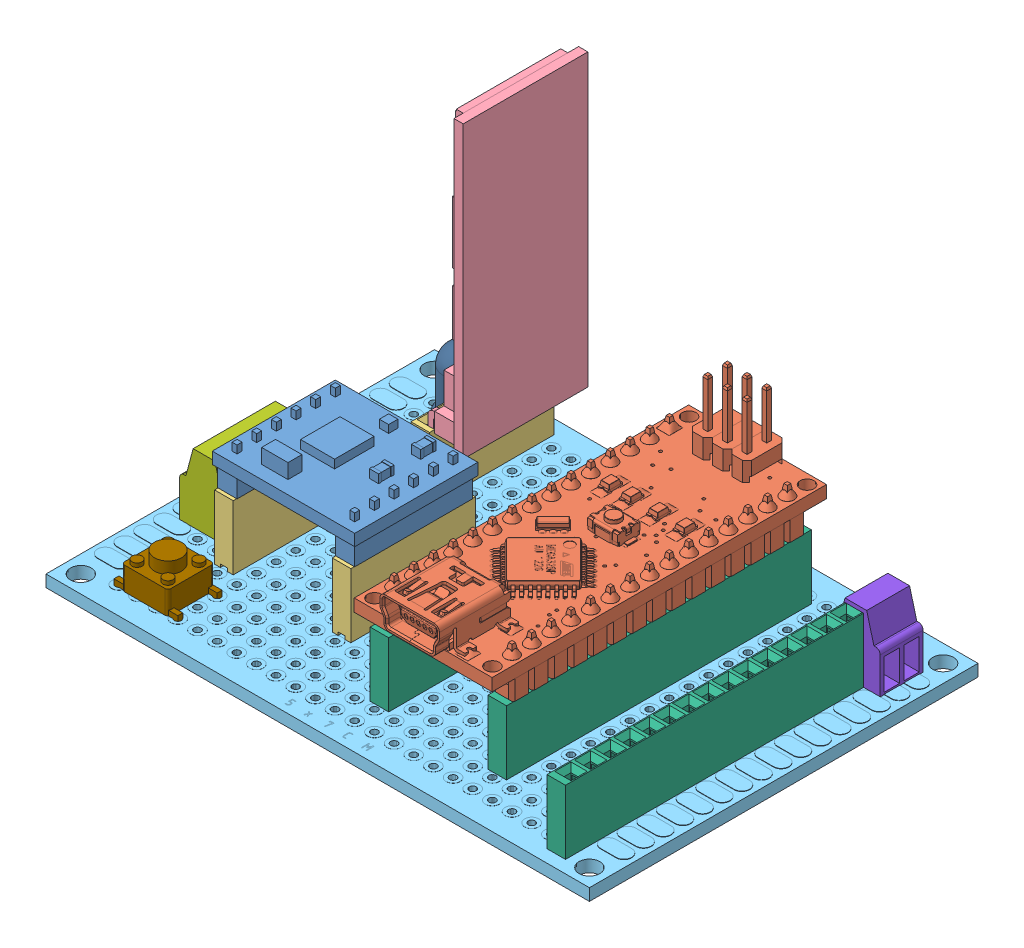
SolidWorks assembly PCB assembly, configuration Default. Lengths in mm.
Overall size (70.2 48.6 50.2).
14 component instances, 10 part files, 20 mates.
Components (placement in the parent):
- DRV8833-1: DRV8833 [Default] at (-16.49 13.955 5.08) size (18.4 11.9 15.9)
- Arduino Nano-1: Arduino Nano [Default] at (16.8088 23.6188 0.3902) x (0 0 1) z (-1 0 0) size (44.95 20.74 17.81)
- Header6P-1: Header6P [Default] at (-24.09 1.555 -1.27) x (0 0 1) z (0 1 0) size (16.1 2.4 11.5)
- Header6P-2: Header6P [Default] at (-8.89 1.555 -1.27) x (0 0 1) z (0 1 0) size (16.1 2.4 11.5)
- HC-05-2: HC-05 [Varsayılan] at (-13.49 46.555 -23.29) x (0 -1 0) z (-1 0 0) size (42.6 16.1 5.9)
- Header6P-3: Header6P [Default] at (-19.04 1.555 -21.59) x (0 0 1) z (0 1 0) size (16.1 2.4 11.5)
- PCB 50 x 70-1: PCB 50 x 70 [Default] x (1 0 0) z (0 1 0) size (70.2 50.2 1.66)
- Header15P-1: Header15P [Default] at (1.2888 2.355 16.51) x (0 0 1) z (0 1 0) size (39.38 2.4 11.5)
- Header15P-2: Header15P [Default] at (16.51 2.355 16.51) x (0 0 1) z (0 1 0) size (39.38 2.4 11.5)
- Header15P-3: Header15P [Default] at (29.21 2.355 -13.97) x (0 0 -1) z (0 1 0) size (39.38 2.4 11.5)
- ScrewTerminal x 4-1: ScrewTerminal x 4 [Default] at (-29.4 1.555 5.08) x (0 0 1) z (-1 0 0) size (10.62 12.4 6.3)
- ScrewTerminal x 2-1: ScrewTerminal x 2 [Default] at (29.41 1.555 -17.78) x (0 0 -1) z (1 0 0) size (5.54 12.4 6.3)
- Push button-1: Push button [Default] at (-25.39 1.555 19.05) size (8.26 7.7 6)
- Led-1: Led [Default] at (-25.39 1.555 -19.05) size (5.8 11.9 5.8)
Mates (geometry in assembly coordinates):
- ProfileCenter6: profile center = 5.6 mm aligned: plane of DRV8833-1 through (45.36 34.005 5.08) normal (0 -1 0); plane of Header6P-1 through (37.76 28.405 11.605) normal (0 -1 0)
- ProfileCenter7: profile center = 5.6 mm aligned: plane of Header6P-2 through (52.96 28.405 11.605) normal (0 -1 0); plane of DRV8833-1 through (45.36 34.005 5.08) normal (0 -1 0)
- ProfileCenter9: profile center = 5.6 mm aligned: plane of HC-05-2 through (48.36 34.005 -23.29) normal (0 -1 0); plane of Header6P-3 through (42.81 28.405 -8.715) normal (0 -1 0)
- ProfileCenter10: profile center = 3.5 mm aligned: plane of Header15P-1 through (63.1388 28.405 16.51) normal (0 -1 0); plane of Arduino Nano-1 through (63.1388 31.905 16.51) normal (0 -1 0)
- ProfileCenter11: profile center = 3.5 mm aligned: plane of Header15P-2 through (78.36 28.405 16.51) normal (0 -1 0); plane of Arduino Nano-1 through (78.36 31.905 16.51) normal (0 -1 0)
- ProfileCenter12: profile center = 3.2 mm anti-aligned: plane of Header15P-2 through (78.36 28.405 16.51) normal (0 -1 0); circle of PCB 50 x 70-1
- ProfileCenter13: profile center = 3.2 mm anti-aligned: plane of Header6P-2 through (52.96 28.405 11.605) normal (0 -1 0); circle of PCB 50 x 70-1
- ProfileCenter15: profile center = 3.2 mm anti-aligned: plane of Header15P-3 through (91.06 28.405 -13.97) normal (0 -1 0); circle of PCB 50 x 70-1
- Parallel2: parallel aligned: plane of Header15P-2 through (17.71 41.0672 15.24) normal (1 0 0); plane of Header15P-3 through (30.41 41.0672 -12.7) normal (1 0 0)
- Parallel3: parallel aligned: plane of Header6P-3 through (-20.24 33.5672 -23.09) normal (-1 0 0); plane of Header15P-1 through (0.0888 41.0672 15.24) normal (-1 0 0)
- ProfileCenter19: profile center = 3.6 mm anti-aligned: plane of ScrewTerminal x 4-1 through (32.45 28.005 5.08) normal (0 -1 0); circle of PCB 50 x 70-1
- Parallel6: parallel anti-aligned: plane of ScrewTerminal x 4-1 through (-29.4 33.5672 5.08) normal (-1 0 0); plane of PCB 50 x 70-1 through (0 32.0122 0) normal (1 0 0)
- ProfileCenter20: profile center = 3.6 mm anti-aligned: plane of ScrewTerminal x 2-1 through (91.26 28.005 -17.78) normal (0 -1 0); circle of PCB 50 x 70-1
- Parallel7: parallel aligned: plane of PCB 50 x 70-1 through (0 32.0122 0) normal (0 0 -1); plane of ScrewTerminal x 2-1 through (29.41 33.5672 -17.78) normal (0 0 -1)
- ProfileCenter21: profile center = 3.2 mm anti-aligned: plane of Push button-1 through (36.46 28.405 19.05) normal (0 -1 0); circle of PCB 50 x 70-1
- ProfileCenter22: profile center = 3.2 mm aligned: plane of Led-1 through (37.73 28.405 -19.05) normal (0 -1 0); circle of PCB 50 x 70-1
- ProfileCenter23: profile center = 3.2 mm anti-aligned: plane of Header6P-3 through (42.81 28.405 -21.415) normal (0 -1 0); circle of PCB 50 x 70-1
- Coincident1: coincident anti-aligned: plane of PCB 50 x 70-1 through (0 0 0) normal (0 0 -1)
- Coincident2: coincident aligned: plane of PCB 50 x 70-1 through (0 0 0) normal (1 0 0)
- Coincident3: coincident aligned: plane of PCB 50 x 70-1 through (0 0 0) normal (0 1 0)
